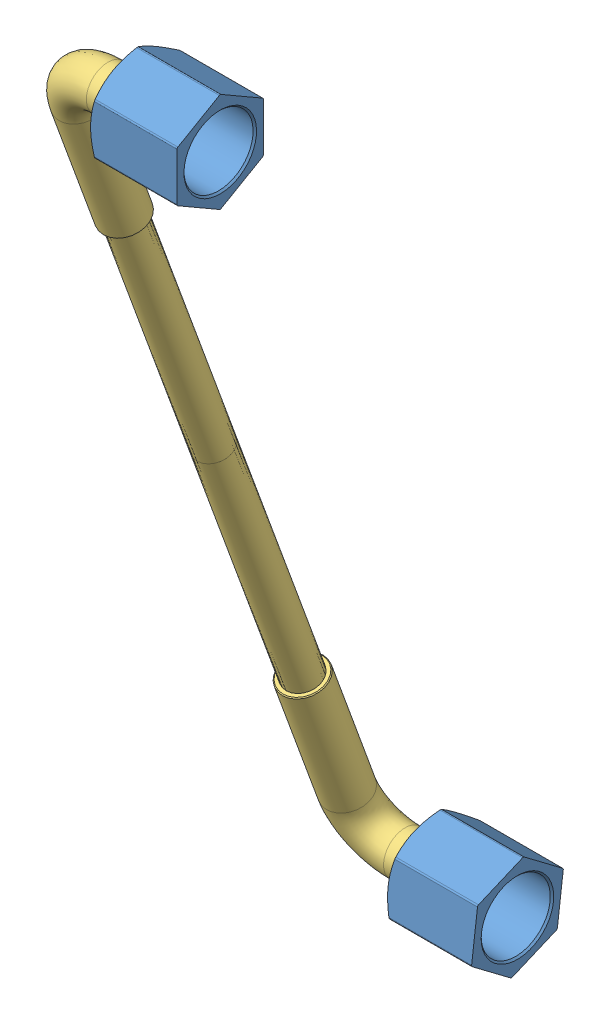
SolidWorks assembly LIVELLOSTATO_COMPLETO, configuration Default. Lengths in mm.
Overall size (20.5 107.09 47.11).
5 component instances, 3 part files, 8 mates.
Components (placement in the parent):
- DADO-1: DADO [Default] at (-38.4207 19.6463 -23.5748) x (0 1 0) z (-1 0 0) size (11.49 10 10)
- GUARNIZIONE-1: GUARNIZIONE [Default] at (-35.4207 19.6463 -23.5748) x (0 0 -1) z (1 0 0) size (8 8 1)
- LIVELLOSTATO-1: LIVELLOSTATO [Default] at (-36.4207 19.6463 -23.5748) x (0 0.34387 -0.939017) z (1 0 0) size (8 108 13.5)
- GUARNIZIONE-2: GUARNIZIONE [Default] at (-35.4207 -74.2555 -57.9618) x (0 0.315486 0.94893) z (1 0 0) size (8 8 1)
- DADO-2: DADO [Default] at (-38.4207 -74.2555 -57.9618) x (0 0.601979 0.798512) z (-1 0 0) size (11.49 10 10)
Mates (geometry in assembly coordinates):
- Concentrico1: concentric anti-aligned: cylinder of DADO-1 through (-38.4217 19.6463 -23.5748) axis (1 0 0) radius 2.75; cylinder of LIVELLOSTATO-1 through (-35.4207 19.6463 -23.5748) axis (-1 0 0) radius 4
- Concentrico2: concentric anti-aligned: cylinder of LIVELLOSTATO-1 through (-35.4207 -74.2555 -57.9618) axis (-1 0 0) radius 4; cylinder of DADO-2 through (-38.4217 -74.2555 -57.9618) axis (1 0 0) radius 2.75
- Coincidente1: coincident anti-aligned: plane of DADO-1 through (-36.4207 19.6463 -23.5748) normal (1 0 0); plane of LIVELLOSTATO-1 through (-36.4207 19.6463 -23.5748) normal (-1 0 0)
- Coincidente2: coincident anti-aligned: plane of LIVELLOSTATO-1 through (-36.4207 -74.2555 -57.9618) normal (-1 0 0); plane of DADO-2 through (-36.4207 -74.2555 -57.9618) normal (1 0 0)
- Concentrico3: concentric anti-aligned: cylinder of DADO-1 through (-36.4207 19.6463 -23.5748) axis (1 0 0) radius 4; cylinder of GUARNIZIONE-1 through (-34.4207 19.6463 -23.5748) axis (-1 0 0) radius 4
- Coincidente3: coincident anti-aligned: plane of GUARNIZIONE-1 through (-35.4207 19.6463 -23.5748) normal (-1 0 0); plane of LIVELLOSTATO-1 through (-35.4207 19.6463 -23.5748) normal (1 0 0)
- Coincidente4: coincident aligned: circle of GUARNIZIONE-2; cylinder of DADO-2 through (-36.4207 -74.2555 -57.9618) axis (1 0 0) radius 4
- Coincidente5: coincident anti-aligned: plane of LIVELLOSTATO-1 through (-35.4207 -74.2555 -57.9618) normal (1 0 0); plane of GUARNIZIONE-2 through (-35.4207 -74.2555 -57.9618) normal (-1 0 0)
